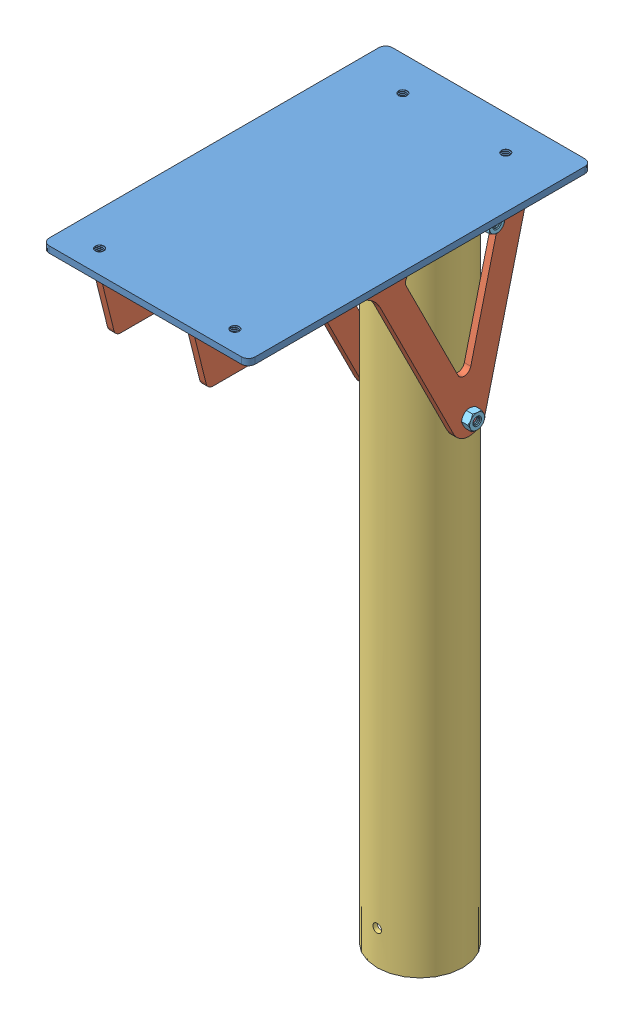
SolidWorks assembly Stilt Assembly, configuration Default. Lengths in mm.
Overall size (152.4 512.77 254).
8 component instances, 5 part files, 18 mates.
Components (placement in the parent):
- Binding mounting plate-1: Binding mounting plate [Default] at (-99.893 9.4336 -122.427) size (152.4 5.06 254)
- Sideplates-1: Sideplates [Default] at (-60.2055 9.4336 131.573) x (0 0 -1) z (1 0 0) size (254 165.03 4.76)
- Sideplates-2: Sideplates [Default] at (8.057 9.4336 131.573) x (0 0 -1) z (1 0 0) size (254 165.03 4.76)
- Top Strut-1: Top Strut [Default] at (-23.693 9.4336 -71.627) x (0 0 1) z (-1 0 0) size (63.5 508 63.5)
- SIDE PLATE BOLT-2: SIDE PLATE BOLT [Default] at (-185.4586 -167.8303 -131.7178) x (1 0 0) z (0 -0.037655 0.999291) size (80.34 12.85 11.13)
- hex nut_ai-1: hex nut_ai [HNUT 0.2500-20-D-S] at (33.3291 -9.6164 -71.627) x (0 0.061718 -0.998094) z (1 0 0) size (11.11 12.83 5.74)
- hex nut_ai-2: hex nut_ai [HNUT 0.2500-20-D-S] at (18.8235 -142.8958 -71.4155) x (0 0.997687 -0.067972) z (1 0 0) size (11.11 12.83 5.74)
- SIDE PLATE BOLT-3: SIDE PLATE BOLT [Default] at (-185.4586 -303.2601 -125.5061) size (80.34 12.85 11.13)
Mates (geometry in assembly coordinates):
- Parallel1: parallel anti-aligned: plane of Binding mounting plate-1 through (52.507 14.1961 -122.427) normal (1 0 0); plane of Sideplates-1 through (-60.2055 -48.9864 12.6165) normal (-1 0 0)
- Coincident1: coincident anti-aligned: plane of Binding mounting plate-1 through (-99.893 9.4336 -122.427) normal (0 -1 0); plane of Sideplates-1 through (-55.443 9.4336 131.573) normal (0 1 0)
- Distance1: distance = 31.75 mm: line of assembly; line of assembly; line of Sideplates-1 through (-55.443 9.4336 131.573) axis (0 0 -1)
- Coincident3: coincident aligned: line of Binding mounting plate-1 through (47.427 9.4336 -122.427) axis (-1 0 0); line of Sideplates-1 through (-55.443 9.4336 -122.427) axis (-1 0 0)
- Parallel2: parallel anti-aligned: plane of Binding mounting plate-1 through (52.507 14.1961 -122.427) normal (1 0 0); plane of Sideplates-2 through (8.057 -48.9864 12.6165) normal (-1 0 0)
- Coincident4: coincident aligned: line of Binding mounting plate-1 through (47.427 9.4336 -122.427) axis (-1 0 0); line of Sideplates-2 through (12.8195 9.4336 -122.427) axis (-1 0 0)
- Coincident5: coincident anti-aligned: plane of Binding mounting plate-1 through (-99.893 9.4336 -122.427) normal (0 -1 0); plane of Sideplates-2 through (12.8195 9.4336 131.573) normal (0 1 0)
- Distance2: distance = 31.75 mm: line of assembly; line of assembly; line of Sideplates-2 through (8.057 9.4336 131.573) axis (0 0 -1)
- Parallel3: parallel anti-aligned: axis of Sideplates-1 through (-59.5705 -9.6164 -71.627) axis (1 0 0); line of Top Strut-1 through (7.8979 -9.6164 -71.627) axis (-1 0 0)
- Coincident6: coincident anti-aligned: plane of Binding mounting plate-1 through (-99.893 9.4336 -122.427) normal (0 -1 0); plane of Top Strut-1 through (-23.693 9.4336 -71.627) normal (0 1 0)
- Tangent2: tangent anti-aligned: plane of Sideplates-1 through (-55.443 -48.9864 12.6165) normal (1 0 0); cylinder of Top Strut-1 through (-23.693 -498.5664 -71.627) axis (0 1 0) radius 31.75
- Concentric1: concentric aligned: circle of Sideplates-1; cylinder of Top Strut-1 through (452.557 -9.6164 -71.627) axis (-1 0 0) radius 3.175
- Coincident7: coincident anti-aligned: line of Sideplates-2 through (8.692 -9.6164 -71.627) axis (1 0 0); line of SIDE PLATE BOLT-2 through (-3.5846 -9.6164 -71.627) axis (-1 0 0)
- Coincident8: coincident anti-aligned: plane of Sideplates-1 through (-60.2055 -48.9864 12.6165) normal (-1 0 0); circle of SIDE PLATE BOLT-2
- Coincident9: coincident anti-aligned: line of SIDE PLATE BOLT-2 through (10.3854 -9.6164 -71.627) axis (-1 0 0); line of hex nut_ai-1 through (28.0498 -9.6164 -71.627) axis (1 0 0)
- Coincident10: coincident anti-aligned: line of Sideplates-2 through (12.8195 -142.8958 -71.4155) axis (-1 0 0); line of hex nut_ai-2 through (14.6822 -142.8958 -71.4155) axis (1 0 0)
- Coincident11: coincident aligned: line of Sideplates-1 through (-55.443 -142.8958 -71.4155) axis (-1 0 0); line of SIDE PLATE BOLT-3 through (-3.5846 -142.8958 -71.4155) axis (-1 0 0)
- Coincident12: coincident anti-aligned: plane of Sideplates-1 through (-60.2055 -48.9864 12.6165) normal (-1 0 0); plane of SIDE PLATE BOLT-3 through (-60.2055 -136.4726 -71.4155) normal (1 0 0)
